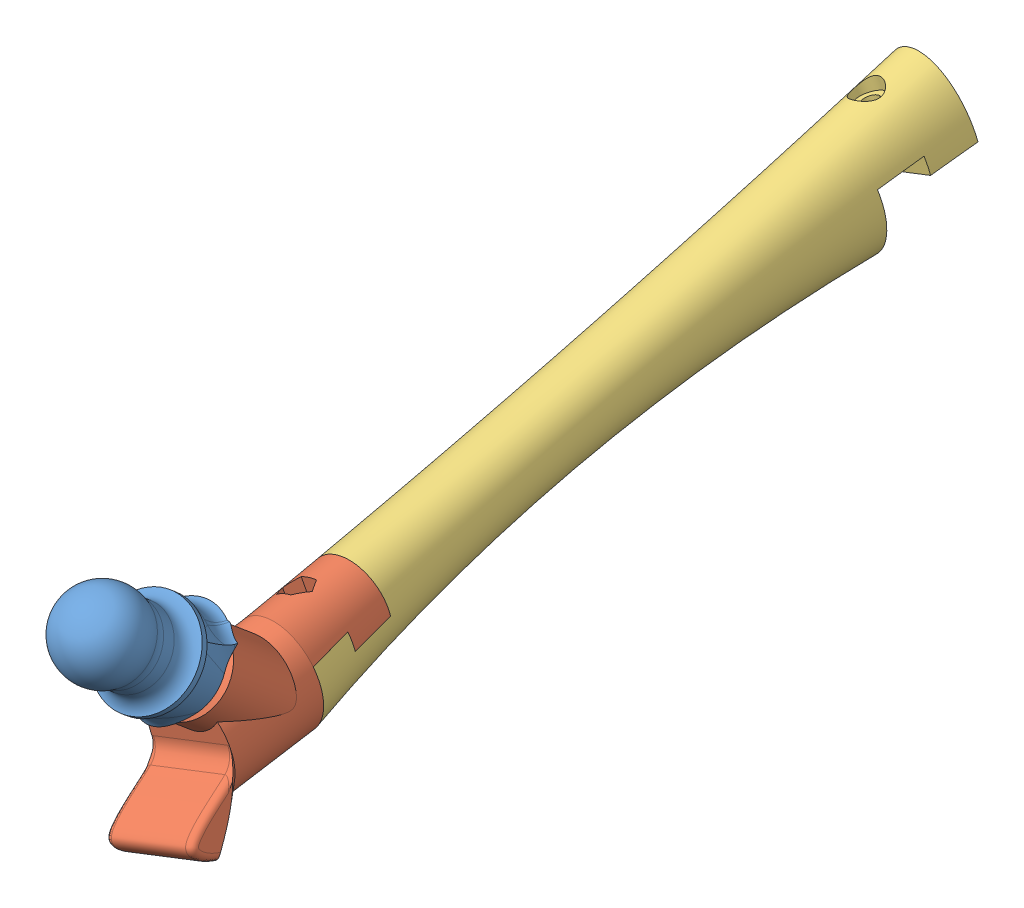
SolidWorks assembly 04_Femur_Left, configuration Default. Lengths in mm.
Overall size (101.49 105.42 393.58).
3 component instances, 3 part files, 6 mates.
Components (placement in the parent):
- 04_01_FK_L_001-1: 04_01_FK_L_001 [Default] at (-46.7228 -402.9121 50.9918) size (38.14 57.65 59.92)
- 04_02_FH_L_001-1: 04_02_FH_L_001 [Default] at (-71.3735 127.5449 4.2394) x (-0.938512 -0.343581 0.033868) z (-0.338704 0.935293 0.1025) size (46.92 105.86 63.35)
- 04_03_FE_L_001-1: 04_03_FE_L_001 [Default] at (-110.4217 141.179 -298.5629) x (0.938512 0.343581 -0.033868) z (0.338704 -0.935293 -0.1025) size (54.81 304.92 50.87)
Mates (geometry in assembly coordinates):
- Coincident2: coincident anti-aligned: plane of 04_02_Femoral_Head_Left-1 through (-75.1403 20.0549 -42.9919) normal (-0.066894 0.084726 -0.994156); plane of 04_03_Femur_Left-1 through (-76.0137 22.4465 -42.7293) normal (0.066894 -0.084726 0.994156)
- Concentric1: concentric aligned: cylinder of 04_03_FE_L_001-1 through (-32.9678 9.202 -27.5926) axis (-0.338704 0.935293 0.1025) radius 3.175; cylinder of 04_02_FH_L_001-1 through (-32.1323 6.8951 -27.8454) axis (-0.338704 0.935293 0.1025) radius 3.175
- Concentric2: concentric anti-aligned: cylinder of 04_01_FK_L_001-1 through (-36.2305 76.8662 58.9075) axis (0 -0.642788 -0.766044) radius 4.953; cylinder of 04_02_FH_L_001-1 through (-36.2305 47.6293 24.0643) axis (0 0.642788 0.766044) radius 3.125
- Coincident3: coincident anti-aligned: plane of 04_02_Femoral_Head_Left-1 through (-74.7425 22.7659 -4.4637) normal (0.338704 -0.935293 -0.1025); plane of 04_03_Femur_Left-1 through (-95.1381 48.5882 -307.4823) normal (-0.338704 0.935293 0.1025)
- Coincident4: coincident anti-aligned: plane of 04_01_Femoral_Knob_Left-1 through (-36.2305 56.9497 35.172) normal (0 -0.642788 -0.766044); plane of 04_02_Femoral_Head_Left-1 through (-36.2305 56.9497 35.172) normal (0 0.642788 0.766044)
- Lock2: lock: unknown of 04_01_Femoral_Knob_Left-1; unknown of 04_02_FH_L_001-1
